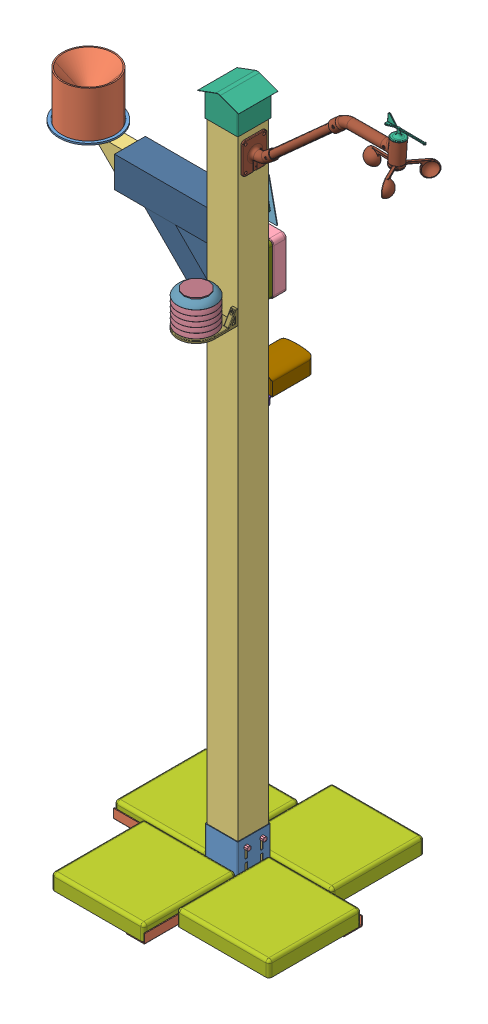
SolidWorks assembly Final, configuration Default. Lengths in mm.
Overall size (1169.98 2361.48 706).
38 component instances, 24 part files, 70 mates.
Components (placement in the parent):
- Mount assem-1: Mount assem [Default] at (356.164 254.9908 570.1027) size (706 140 706)
  - Mount V2-1: Mount V2 [Default] at (-66.6913 -82.2506 43.5149) size (155 140 145)
  - L-beam-1: L-beam [Default] at (-15.6913 -80.2506 396.5149) x (-1 0 0) z (0 0 -1) size (60 30 300)
  - L-beam-2: L-beam [Default] at (286.3087 -80.2506 -7.4851) x (0 0 1) z (-1 0 0) size (60 30 300)
  - L-beam-3: L-beam [Default] at (-117.6913 -80.2506 -309.4851) size (60 30 300)
  - L-beam-4: L-beam [Default] at (-419.6913 -80.2506 94.5149) x (0 0 -1) z (1 0 0) size (60 30 300)
- Wood pole 100x100x2200-1: Wood pole 100x100x2200 [Default] at (290.4727 174.7402 614.6176) size (100 2200 100)
- Thru axle + nut 10x100-1: Thru axle + nut 10x100 [Default] at (232.4727 286.2402 639.6176) x (0 -1 0) z (1 0 0) size (13 13 120)
- Thru axle + nut 10x100-2: Thru axle + nut 10x100 [Default] at (352.4727 286.2402 587.6176) x (0 0 1) z (-1 0 0) size (13 13 120)
- LOGO tryout V2-1: LOGO tryout V2 [Default] at (287.9727 2294.7402 555.1176) x (-1 0 0) z (0 0 -1) size (95 69 2)
- Top with logo-1: Top with logo [Default] at (288.4727 2297.7402 668.6176) size (133.17 99.41 128)
- Brick 300x300-1: Brick 300x300 [Default] at (492.4727 177.7402 715.6176) size (300 50 300)
- Brick 300x300-2: Brick 300x300 [Default] at (187.4727 177.7402 816.6176) size (300 50 300)
- Brick 300x300-3: Brick 300x300 [Default] at (391.4727 177.7402 410.6176) size (300 50 300)
- Brick 300x300-4: Brick 300x300 [Default] at (86.4727 177.7402 511.6176) size (300 50 300)
- Arduino case V3 Underside-1: Arduino case V3 Underside [Default] at (290.4727 1506.1995 489.6176) size (101.6 78.97 140.56)
- Arduino case V3 Upperside-1: Arduino case V3 Upperside [Default] at (291.2727 1506.1995 490.4176) size (107.29 69.73 154.57)
- Wood-1: Wood [Default] at (240.4727 1994.7402 614.6176) x (0 0 -1) z (0 1 0) size (100 300 302.31)
- Wind-1: Wind [Default] at (609.6037 2444.1636 623.234) x (1 0 0) z (0 -0.076336 -0.997082) size (509.68 311.51 184.53)
- Base temp-2: Base temp [Default] at (280.4727 1771.427 739.6176) x (0 0 -1) z (1 0 0) size (135 107.55 120)
- disk-2: disk [Default] at (280.4727 1774.427 739.6176) x (0 0 -1) z (1 0 0) size (119.3 37.5 119.3)
- Top-1: Top [Default] at (280.4727 1835.927 739.6176) x (0 0 -1) z (1 0 0) size (119.42 17.5 119.42)
- disk-3: disk [Default] at (280.4727 1790.427 739.6176) x (0 0 -1) z (1 0 0) size (119.3 37.5 119.3)
- disk-4: disk [Default] at (280.4727 1806.427 739.6176) x (0 0 -1) z (1 0 0) size (119.3 37.5 119.3)
- disk-5: disk [Default] at (280.4727 1822.427 739.6176) x (0 0 -1) z (1 0 0) size (119.3 37.5 119.3)
- disk-6: disk [Default] at (280.4727 1838.427 739.6176) x (0 0 -1) z (1 0 0) size (119.3 37.5 119.3)
- houder zonnepanneel v2-1: houder zonnepanneel v2 [Default] at (287.9811 2042.2402 559.6176) size (103.53 267.55 55.06)
- houder zonnepanneel v2-Cut-Extrude141-1: houder zonnepanneel v2-Cut-Extrude141 [Default] at (292.1067 1995.5286 559.6176) size (96.13 161.13 50.06)
- rain_sensor_solidworks-1: rain_sensor_solidworks [Default] at (-194.5273 2049.7402 614.6176) x (0 0 1) z (0 1 0) size (190 230 252)
  - assemblagereduit.CATProduct-1: assemblagereduit.CATProduct [Default] at origin size (190 230 252)
    - supportV2.CATPart-1: supportV2.CATPart [Default] at origin size (112 95 65)
    - spoonV2.CATPart-1: spoonV2.CATPart [Default] at (-0.913 17.5 25.602) x (0 -1 0) z (-0.331106 0 0.943593) size (49 108.76 30.11)
    - baseV2.CATPart-1: baseV2.CATPart [Default] at (0 0 -5) size (190 190 11)
    - boxV2.CATPart-1: boxV2.CATPart [Default] at (0 0 147) size (168.07 168.28 156)
    - mat.CATPart-1: mat.CATPart [Default] at (-25 135 -5) size (50 210 100)
- houder zonnepanneel v2-Surface-Offset2-1: houder zonnepanneel v2-Surface-Offset2 [Default] at (291.1067 1996.5286 559.6176) size (104.6 169.6 42.06)
- Zonnepaneel-1: Zonnepaneel [Default] at (295.4727 2057.7377 550.7258) x (1 0 0) z (0 0.984808 0.173648) size (90 3 160)
- wind 32-1: wind 32 [Default] at (814.6468 2504.2293 592.8306) x (-0.999942 -0.00082 -0.010714) z (0.010745 -0.076331 -0.997025) size (125.59 51.34 44)
Mates (geometry in assembly coordinates):
- Coincident1: coincident anti-aligned: plane of Mount assem-1/Mount V2-1 through (340.4727 312.7402 664.6176) normal (0 0 -1); plane of Wood pole 100x100x2200-1 through (340.4727 2374.7402 664.6176) normal (0 0 1)
- Coincident2: coincident anti-aligned: plane of Mount assem-1/Mount V2-1 through (340.4727 312.7402 664.6176) normal (-1 0 0); plane of Wood pole 100x100x2200-1 through (340.4727 2374.7402 664.6176) normal (1 0 0)
- Coincident3: coincident anti-aligned: plane of Mount assem-1/Mount V2-1 through (289.4727 174.7402 613.6176) normal (0 1 0); plane of Wood pole 100x100x2200-1 through (290.4727 174.7402 614.6176) normal (0 -1 0)
- Coincident4: coincident anti-aligned: plane of Mount assem-1/Mount V2-1 through (342.4727 312.7402 666.6176) normal (1 0 0); plane of Thru axle + nut 10x100-1 through (342.4727 286.2402 639.6176) normal (-1 0 0)
- Coincident7: coincident: point of Mount assem-1/Mount V2-1; point of Thru axle + nut 10x100-1
- Coincident8: coincident: line of Mount assem-1/Mount V2-1 through (342.4727 254.7402 642.6176) axis (0 1 0); unknown of Thru axle + nut 10x100-1
- Coincident9: coincident anti-aligned: plane of Mount assem-1/Mount V2-1 through (342.4727 312.7402 666.6176) normal (1 0 0); plane of Thru axle + nut 10x100-2 through (342.4727 286.2402 587.6176) normal (-1 0 0)
- Coincident10: coincident anti-aligned: line of Mount assem-1/Mount V2-1 through (342.4727 292.7402 586.6176) axis (0 0 1); line of Thru axle + nut 10x100-2 through (342.4727 292.7402 590.6176) axis (0 0 -1)
- Coincident11: coincident: point of Mount assem-1/Mount V2-1; point of Thru axle + nut 10x100-2
- Coincident12: coincident anti-aligned: plane of Wood pole 100x100x2200-1 through (290.4727 2374.7402 614.6176) normal (0 1 0); plane of Top with logo-1 through (288.4727 2374.7402 668.6176) normal (0 -1 0)
- Coincident13: coincident anti-aligned: plane of Wood pole 100x100x2200-1 through (340.4727 2374.7402 664.6176) normal (0 0 1); plane of Top with logo-1 through (236.4727 2266.7402 664.6176) normal (0 0 -1)
- Coincident14: coincident anti-aligned: plane of Wood pole 100x100x2200-1 through (340.4727 2374.7402 664.6176) normal (1 0 0); plane of Top with logo-1 through (340.4727 2374.7402 663.6176) normal (-1 0 0)
- Coincident18: coincident anti-aligned: plane of LOGO tryout V2-1 through (287.9727 2294.7402 557.6176) normal (0 0 1); plane of Top with logo-1 through (234.4727 2294.7402 557.6176) normal (0 0 -1)
- Coincident19: coincident aligned: line of LOGO tryout V2-1 through (240.4727 2294.7402 557.6176) axis (1 0 0); line of Top with logo-1 through (236.4727 2294.7402 557.6176) axis (1 0 0)
- Distance2: distance = 4 mm: line of LOGO tryout V2-1 through (240.4727 2363.7402 557.6176) axis (0 -1 0); line of Top with logo-1 through (236.4727 2294.7402 557.6176) axis (0 1 0)
- Coincident27: coincident anti-aligned: plane of Mount assem-1/L-beam-2 through (342.4727 177.7402 565.6176) normal (0 0 1); plane of Brick 300x300-1 through (642.4727 227.7402 565.6176) normal (0 0 -1)
- Coincident28: coincident anti-aligned: plane of Mount assem-1/L-beam-2 through (342.4727 177.7402 622.6176) normal (0 1 0); plane of Brick 300x300-1 through (492.4727 177.7402 715.6176) normal (0 -1 0)
- Coincident29: coincident anti-aligned: plane of Mount assem-1/Mount V2-1 through (342.4727 312.7402 666.6176) normal (1 0 0); plane of Brick 300x300-1 through (342.4727 227.7402 865.6176) normal (-1 0 0)
- Coincident30: coincident anti-aligned: plane of Mount assem-1/L-beam-3 through (298.4727 177.7402 560.6176) normal (0 1 0); plane of Brick 300x300-3 through (391.4727 177.7402 410.6176) normal (0 -1 0)
- Coincident31: coincident anti-aligned: plane of Mount assem-1/L-beam-3 through (241.4727 177.7402 560.6176) normal (1 0 0); plane of Brick 300x300-3 through (241.4727 227.7402 560.6176) normal (-1 0 0)
- Coincident32: coincident anti-aligned: plane of Mount assem-1/Mount V2-1 through (342.4727 312.7402 560.6176) normal (0 0 -1); plane of Brick 300x300-3 through (541.4727 227.7402 560.6176) normal (0 0 1)
- Coincident33: coincident anti-aligned: plane of Mount assem-1/L-beam-4 through (236.4727 177.7402 604.6176) normal (0 1 0); plane of Brick 300x300-4 through (86.4727 177.7402 511.6176) normal (0 -1 0)
- Coincident34: coincident anti-aligned: plane of Mount assem-1/Mount V2-1 through (236.4727 312.7402 666.6176) normal (-1 0 0); plane of Brick 300x300-4 through (236.4727 227.7402 661.6176) normal (1 0 0)
- Coincident35: coincident anti-aligned: plane of Mount assem-1/L-beam-4 through (236.4727 177.7402 661.6176) normal (0 0 -1); plane of Brick 300x300-4 through (236.4727 227.7402 661.6176) normal (0 0 1)
- Coincident36: coincident anti-aligned: plane of Mount assem-1/L-beam-1 through (280.4727 177.7402 666.6176) normal (0 1 0); plane of Brick 300x300-2 through (187.4727 177.7402 816.6176) normal (0 -1 0)
- Coincident37: coincident anti-aligned: plane of Mount assem-1/L-beam-1 through (337.4727 177.7402 666.6176) normal (-1 0 0); plane of Brick 300x300-2 through (337.4727 227.7402 966.6176) normal (1 0 0)
- Coincident38: coincident anti-aligned: plane of Mount assem-1/Mount V2-1 through (342.4727 312.7402 666.6176) normal (0 0 1); plane of Brick 300x300-2 through (337.4727 227.7402 666.6176) normal (0 0 -1)
- Coincident39: coincident anti-aligned: plane of Wood pole 100x100x2200-1 through (340.4727 2374.7402 564.6176) normal (0 0 -1); plane of Arduino case V3 Underside-1 through (290.4727 1511.1995 564.6176) normal (0 0 1)
- Coincident40: coincident aligned: plane of Wood pole 100x100x2200-1 through (240.4727 2374.7402 664.6176) normal (-1 0 0); plane of Arduino case V3 Underside-1 through (240.4727 1509.1995 554.6176) normal (-1 0 0)
- Coincident41: coincident anti-aligned: plane of Arduino case V3 Underside-1 through (240.4727 1509.1995 554.6176) normal (-1 0 0); plane of Arduino case V3 Upperside-1 through (240.4727 1509.1995 555.4176) normal (1 0 0)
- Coincident42: coincident anti-aligned: plane of Arduino case V3 Underside-1 through (340.4727 1509.1995 424.6176) normal (0 0 -1); plane of Arduino case V3 Upperside-1 through (341.2727 1509.1995 424.6176) normal (0 0 1)
- Coincident48: coincident: plane of Arduino case V3 Underside-1; plane of Arduino case V3 Upperside-1 through (342.0727 1508.6995 555.4176) normal (0 -1 0)
- Coincident49: coincident anti-aligned: plane of Wood pole 100x100x2200-1 through (240.4727 2374.7402 664.6176) normal (-1 0 0); plane of Wood-1 through (240.4727 1994.7402 614.6176) normal (1 0 0)
- Perpendicular1: perpendicular: line of Wood pole 100x100x2200-1 through (240.4727 2374.7402 564.6176) axis (0 -1 0); line of Wood-1 through (240.4727 1742.427 664.6176) axis (0 0 -1)
- Distance3: distance = 250 mm anti-aligned: plane of Wood-1 through (-59.5273 2044.7402 564.6176) normal (0 1 0); plane of Top with logo-1 through (238.4727 2294.7402 666.6176) normal (0 -1 0)
- Distance5: distance = 120 mm aligned: plane of Top with logo-1 through (238.4727 2294.7402 666.6176) normal (0 -1 0); plane of Wind-1 through (346.4727 2174.7402 654.6176) normal (0 -1 0)
- Concentric1: concentric aligned: cylinder of Base temp-2 through (259.2595 1869.427 718.4044) axis (0 -1 0) radius 5; cylinder of disk-2 through (259.2595 1794.427 718.4044) axis (0 -1 0) radius 5.4
- Distance8: distance = 25 mm aligned: plane of disk-2 through (280.4727 1794.427 739.6176) normal (0 1 0); plane of Base temp-2 through (283.7227 1769.427 728.4661) normal (0 1 0)
- Concentric2: concentric aligned: cylinder of Base temp-2 through (259.2595 1869.427 718.4044) axis (0 -1 0) radius 5; cylinder of disk-3 through (259.2595 1810.427 718.4044) axis (0 -1 0) radius 5.4
- Coincident58: coincident anti-aligned: plane of disk-2 through (280.4727 1806.927 739.6176) normal (0 1 0); plane of disk-3 through (280.4727 1806.927 739.6176) normal (0 -1 0)
- Concentric3: concentric aligned: cylinder of Base temp-2 through (301.6859 1869.427 718.4044) axis (0 -1 0) radius 5; cylinder of disk-4 through (301.6859 1826.427 718.4044) axis (0 -1 0) radius 5.4
- Coincident59: coincident anti-aligned: plane of disk-3 through (280.4727 1822.927 739.6176) normal (0 1 0); plane of disk-4 through (280.4727 1822.927 739.6176) normal (0 -1 0)
- Concentric4: concentric aligned: cylinder of Base temp-2 through (301.6859 1869.427 718.4044) axis (0 -1 0) radius 5; cylinder of disk-5 through (301.6859 1842.427 718.4044) axis (0 -1 0) radius 5.4
- Coincident60: coincident anti-aligned: plane of disk-4 through (280.4727 1838.927 739.6176) normal (0 1 0); plane of disk-5 through (280.4727 1838.927 739.6176) normal (0 -1 0)
- Concentric5: concentric aligned: cylinder of Base temp-2 through (301.6859 1869.427 718.4044) axis (0 -1 0) radius 5; cylinder of disk-6 through (301.6859 1858.427 718.4044) axis (0 -1 0) radius 5.4
- Coincident61: coincident anti-aligned: plane of disk-5 through (280.4727 1854.927 739.6176) normal (0 1 0); plane of disk-6 through (280.4727 1854.927 739.6176) normal (0 -1 0)
- Coincident62: coincident anti-aligned: plane of Base temp-2 through (301.6859 1869.427 718.4044) normal (0 1 0); plane of Top-1 through (280.4727 1869.427 739.6176) normal (0 -1 0)
- Concentric6: concentric aligned: circle of Top-1; circle of disk-6
- Coincident63: coincident anti-aligned: plane of Wood pole 100x100x2200-1 through (340.4727 2374.7402 664.6176) normal (0 0 1); plane of Base temp-2 through (296.1103 1672.8485 664.6176) normal (0 0 -1)
- Coincident67: coincident anti-aligned: plane of Wood pole 100x100x2200-1 through (340.4727 2374.7402 664.6176) normal (1 0 0); plane of Wind-1 through (340.4727 2224.7402 614.6176) normal (-1 0 0)
- Distance9: distance = 10 mm aligned: plane of Wind-1 through (346.4727 2274.7402 574.6176) normal (0 0 -1); plane of Wood pole 100x100x2200-1 through (340.4727 2374.7402 564.6176) normal (0 0 -1)
- Coincident69: coincident anti-aligned: plane of Wood pole 100x100x2200-1 through (340.4727 2374.7402 564.6176) normal (0 0 -1); plane of houder zonnepanneel v2-1 through (315.4811 2079.7402 564.6176) normal (0 0 1)
- Distance10: distance = 15 mm: line of houder zonnepanneel v2-1 through (325.4811 2079.7402 564.1176) axis (0 -1 0); line of Wood pole 100x100x2200-1 through (340.4727 2374.7402 564.6176) axis (0 -1 0)
- Coincident71: coincident anti-aligned: plane of Wood pole 100x100x2200-1 through (340.4727 2374.7402 564.6176) normal (0 0 -1); plane of houder zonnepanneel v2-Cut-Extrude141-1 through (319.6067 2033.0286 564.6176) normal (0 0 1)
- Distance11: distance = 1 mm: line of houder zonnepanneel v2-Cut-Extrude141-1 through (339.6067 1929.7402 564.1176) axis (0 -1 0); line of Wood pole 100x100x2200-1 through (340.4727 2374.7402 564.6176) axis (0 -1 0)
- Coincident76: coincident: point of Wood-1; point of Base temp-2
- Coincident77: coincident anti-aligned: line of Wood pole 100x100x2200-1 through (340.4727 2374.7402 664.6176) axis (0 -1 0); line of Base temp-2 through (340.4727 1762.427 664.6176) axis (0 1 0)
- Coincident78: coincident anti-aligned: plane of Wood-1 through (-59.5273 1994.7402 614.6176) normal (-1 0 0); plane of rain_sensor_solidworks-1/assemblagereduit.CATProduct-1/mat.CATPart-1 through (-59.5273 1944.7402 589.6176) normal (1 0 0)
- Parallel5: parallel aligned: plane of Wood-1 through (-59.5273 2044.7402 564.6176) normal (0 0 -1); plane of rain_sensor_solidworks-1/assemblagereduit.CATProduct-1/mat.CATPart-1 through (-59.5273 2044.7402 589.6176) normal (0 0 -1)
- Distance13: distance = 25 mm: line of rain_sensor_solidworks-1/assemblagereduit.CATProduct-1/mat.CATPart-1 through (-59.5273 1944.7402 589.6176) axis (0 1 0); line of Wood-1 through (-59.5273 2044.7402 564.6176) axis (0 -1 0)
- Coincident82: coincident aligned: line of Wood-1 through (-59.5273 1944.7402 564.6176) axis (0 0 1); line of rain_sensor_solidworks-1/assemblagereduit.CATProduct-1/mat.CATPart-1 through (-59.5273 1944.7402 589.6176) axis (0 0 1)
- Coincident83: coincident anti-aligned: plane of houder zonnepanneel v2-Cut-Extrude141-1 through (292.1067 1779.7402 564.6176) normal (0 -1 0); plane of houder zonnepanneel v2-Surface-Offset2-1 through (291.1067 1779.7402 564.6176) normal (0 1 0)
- Coincident84: coincident anti-aligned: plane of houder zonnepanneel v2-Cut-Extrude141-1 through (339.6067 1995.5286 564.6176) normal (1 0 0); plane of houder zonnepanneel v2-Surface-Offset2-1 through (339.6067 1996.5286 564.6176) normal (-1 0 0)
- Coincident85: coincident anti-aligned: plane of houder zonnepanneel v2-Cut-Extrude141-1 through (292.1067 1995.5286 514.6176) normal (0 0 -1); plane of houder zonnepanneel v2-Surface-Offset2-1 through (328.6067 1870.7402 514.6176) normal (0 0 1)
- Coincident86: coincident anti-aligned: plane of houder zonnepanneel v2-1 through (231.4811 1994.7402 539.6176) normal (0 0.173648 -0.984808); plane of Zonnepaneel-1 through (295.4727 2057.7377 550.7258) normal (0 -0.173648 0.984808)
- Coincident87: coincident aligned: plane of Wood pole 100x100x2200-1 through (340.4727 2374.7402 664.6176) normal (1 0 0); plane of Zonnepaneel-1 through (340.4727 2136.8696 562.648) normal (1 0 0)
- Coincident88: coincident: plane of Wood pole 100x100x2200-1 through (340.4727 2374.7402 564.6176) normal (0 0 -1); line of Zonnepaneel-1 through (252.4727 2136.5223 564.6176) axis (1 0 0)
- Coincident89: coincident anti-aligned: plane of Wood-1 through (-59.5273 1944.7402 564.6176) normal (0 -1 0); plane of houder zonnepanneel v2-Surface-Offset2-1 through (291.1067 1944.7402 564.6176) normal (0 1 0)
- Concentric7: concentric aligned: cylinder of Wind-1 through (791.4906 2480.2803 594.4144) axis (0 0.997082 -0.076336) radius 21; cylinder of wind 32-1 through (791.4906 2481.2774 594.3381) axis (0 0.997082 -0.076336) radius 21.25
- Coincident90: coincident anti-aligned: plane of Wind-1 through (791.4906 2483.2715 594.1854) normal (0 0.997082 -0.076336); plane of wind 32-1 through (791.4906 2483.2715 594.1854) normal (0 -0.997082 0.076336)
